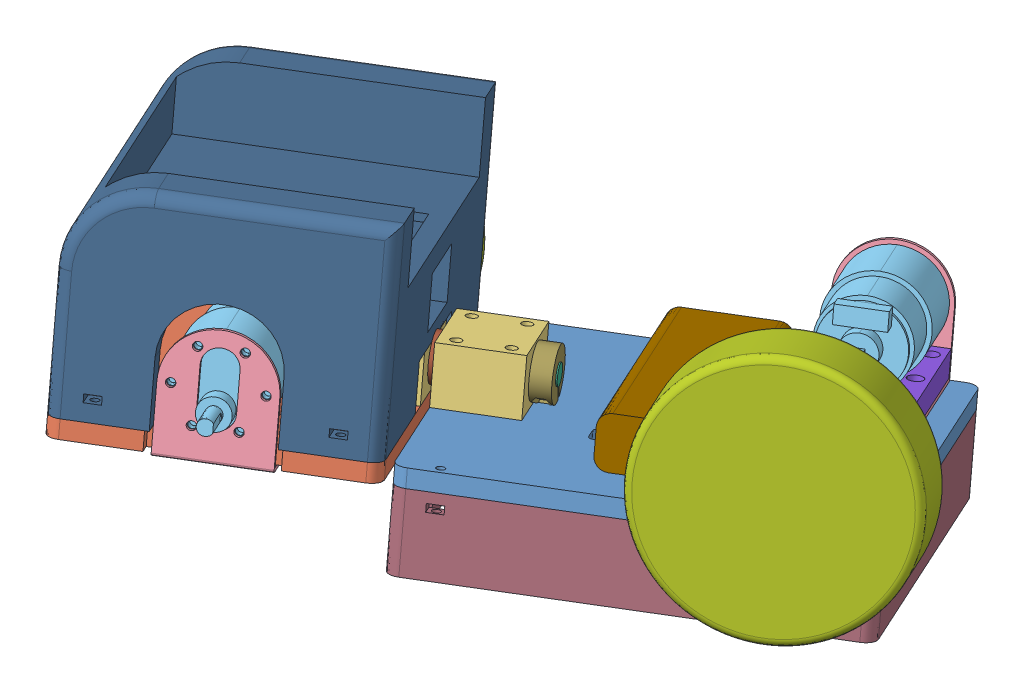
SolidWorks assembly 整车装配体, configuration 默认. Lengths in mm.
Overall size (378.96 184.31 287).
28 component instances, 16 part files, 74 mates.
Components (placement in the parent):
- 底盘-1: 底盘 [默认] at (692.6864 582.8869 540.7098) x (-0.51896 -0.27372 -0.809789) z (0.844115 -0.014792 -0.535958) size (150 7 160)
- 前底盘-1: 前底盘 [默认] at (576.1985 584.9282 614.672) x (0.51896 0.27372 0.809789) z (-0.844115 0.014792 0.535958) size (150 7 110)
- 轴承滑块-1: 轴承滑块 [默认] at (633.9119 611.7376 568.6239) x (0.51896 0.27372 0.809789) z (0.844115 -0.014792 -0.535958) size (34 22 30)
- 轴承滑块-2: 轴承滑块 [默认] at (606.0561 612.2257 586.3106) x (-0.51896 -0.27372 -0.809789) z (-0.844115 0.014792 0.535958) size (34 22 30)
- 37电机支架-1: 37电机支架 [默认] at (554.8799 562.9346 544.3865) x (0.51896 0.27372 0.809789) z (-0.844115 0.014792 0.535958) size (41 45.5 40)
- mg513-30F_电机-1: mg513-30F_电机 [默认] at (610.5897 627.8536 667.6522) x (-0.134724 0.961696 -0.238728) z (-0.844115 0.014792 0.535958) size (36.6 73.4 36.6)
- 37电机支架-2: 37电机支架 [默认] at (712.4284 568.328 441.5972) x (0.51896 0.27372 0.809789) z (-0.844115 0.014792 0.535958) size (41 45.5 40)
- mg513-30F_电机-2: mg513-30F_电机 [默认] at (768.1382 633.2471 564.8629) x (-0.134724 0.961696 -0.238728) z (-0.844115 0.014792 0.535958) size (36.6 73.4 36.6)
- 37电机支架-3: 37电机支架 [默认] at (755.4698 609.4303 582.8843) x (-0.51896 -0.27372 -0.809789) z (0.844115 -0.014792 -0.535958) size (41 45.5 40)
- mg513-30F_电机-3: mg513-30F_电机 [默认] at (692.8891 593.5577 447.4435) x (-0.134724 0.961696 -0.238728) z (0.844115 -0.014792 -0.535958) size (36.6 73.4 36.6)
- 37电机支架-4: 37电机支架 [默认] at (597.9213 604.0368 685.6736) x (-0.51896 -0.27372 -0.809789) z (0.844115 -0.014792 -0.535958) size (41 45.5 40)
- mg513-30F_电机-4: mg513-30F_电机 [默认] at (535.3406 588.1642 550.2328) x (-0.134724 0.961696 -0.238728) z (0.844115 -0.014792 -0.535958) size (36.6 73.4 36.6)
- 连接轴-1: 连接轴 [默认] at (587.2793 602.0021 601.7996) x (0.844115 -0.014792 -0.535958) z (-0.047885 0.993545 -0.102839) size (80 8 8)
- 轮子-1: 轮子 [默认] at (674.6306 576.6982 419.1524) x (0.51896 0.27372 0.809789) z (-0.251206 -0.856676 0.450556) size (30 98 98) (hidden)
- 轮子-2: 轮子 [默认] at (630.7343 631.2494 699.2855) x (-0.51896 -0.27372 -0.809789) z (0.272781 -0.950844 0.146585) size (30 98 98) (hidden)
- 轮子-3: 轮子 [默认] at (788.2828 636.6429 596.4962) x (-0.51896 -0.27372 -0.809789) z (-0.841816 -0.000828 0.539764) size (30 98 98)
- 轮子-4: 轮子 [默认] at (517.0821 571.3047 521.9417) x (0.51896 0.27372 0.809789) z (0.602725 0.554588 -0.57372) size (30 98 98)
- 电机支撑件-3: 电机支撑件 [默认] at (771.3716 610.1664 570.5924) x (-0.51896 -0.27372 -0.809789) z (0.844115 -0.014792 -0.535958) size (145 11.59 40)
- 电机支撑件_前-1: 电机支撑件_前 [默认] at (612.678 612.9474 671.3525) x (-0.51896 -0.27372 -0.809789) z (0.844115 -0.014792 -0.535958) size (145 11.5 40) (hidden)
- 电池-1: 电池 [默认] at (681.0486 594.1442 479.5269) x (0.51896 0.27372 0.809789) z (0.844115 -0.014792 -0.535958) size (106 20 42)
- pcb板子-1: pcb板子 [默认] at (397.0351 450.2511 715.159) x (0.51896 0.27372 0.809789) z (0.844115 -0.014792 -0.535958) size (100 3 100) (hidden)
- 前载物台-1: 前载物台 [默认] at (575.2555 591.6601 613.0009) x (0.51896 0.27372 0.809789) z (-0.844115 0.014792 0.535958) size (150 80 110)
- 轴固定块2-1: 轴固定块2 [默认] at (656.2905 590.2401 561.5489) x (0.51896 0.27372 0.809789) z (-0.844115 0.014792 0.535958) size (34 22 8) (hidden)
- 中间挡块-1: 中间挡块 [默认] at (622.7322 601.3808 579.2893) x (0.5361 0.008129 0.844115) z (-0.844115 0.014792 0.535958) size (18 18 3)
- 轴固定块2-2: 轴固定块2 [默认] at (596.3583 591.2903 599.6019) x (0.51896 0.27372 0.809789) z (-0.844115 0.014792 0.535958) size (34 22 8) (hidden)
- 轴档块-1: 轴档块 [默认] at (654.3865 600.8261 559.1909) x (0.533607 -0.074295 0.842463) z (-0.844115 0.014792 0.535958) size (20 19.97 7.5)
- 轴档块-2: 轴档块 [默认] at (594.8764 601.869 596.9759) x (0.533607 -0.074295 0.842463) z (-0.844115 0.014792 0.535958) size (20 19.97 7.5)
- hou载物台-3: hou载物台 [默认] at (696.7281 554.036 547.8716) x (0.51896 0.27372 0.809789) z (-0.844115 0.014792 0.535958) size (150 30 160)
Mates (geometry in assembly coordinates):
- 重合1: coincident anti-aligned: plane of 前底盘-1 through (575.2555 591.6601 613.0009) normal (-0.134724 0.961696 -0.238728); plane of 轴承滑块-2 through (609.0201 591.0684 591.5626) normal (0.134724 -0.961696 0.238728)
- 同心1: concentric anti-aligned: cylinder of 前底盘-1 through (611.3327 580.9188 578.6926) axis (-0.134724 0.961696 -0.238728) radius 2.2; cylinder of 轴承滑块-2 through (607.4257 608.808 571.7695) axis (0.134724 -0.961696 0.238728) radius 2.15
- 同心2: concentric anti-aligned: cylinder of 前底盘-1 through (608.5936 587.7543 607.7748) axis (-0.134724 0.961696 -0.238728) radius 2.2; cylinder of 轴承滑块-2 through (604.6866 615.6435 600.8516) axis (0.134724 -0.961696 0.238728) radius 2.15
- 重合2: coincident anti-aligned: plane of 底盘-1 through (691.7433 589.6188 539.0387) normal (-0.134724 0.961696 -0.238728); plane of 轴承滑块-1 through (636.8759 590.5803 573.876) normal (0.134724 -0.961696 0.238728)
- 同心5: concentric anti-aligned: cylinder of 底盘-1 through (651.6435 586.9999 580.4409) axis (-0.134724 0.961696 -0.238728) radius 2.2; cylinder of 轴承滑块-1 through (647.7365 614.8891 573.5178) axis (0.134724 -0.961696 0.238728) radius 2.15
- 同心6: concentric anti-aligned: cylinder of 底盘-1 through (623.9944 580.6969 570.6532) axis (-0.134724 0.961696 -0.238728) radius 2.02; cylinder of 轴承滑块-1 through (620.0874 608.5861 563.7301) axis (0.134724 -0.961696 0.238728) radius 2.15
- 同心7: concentric anti-aligned: cylinder of 轴承滑块-1 through (622.7322 601.3808 579.2893) axis (0.844115 -0.014792 -0.535958) radius 4; cylinder of 轴承滑块-2 through (620.1998 601.4252 580.8972) axis (-0.844115 0.014792 0.535958) radius 4
- 重合8: coincident anti-aligned: plane of 底盘-1 through (691.7433 589.6188 539.0387) normal (-0.134724 0.961696 -0.238728); plane of 37电机支架-3 through (734.1925 598.2078 549.683) normal (0.134724 -0.961696 0.238728)
- 同心16: concentric anti-aligned: cylinder of 底盘-1 through (768.8312 593.1479 539.0739) axis (-0.134724 0.961696 -0.238728) radius 1.65; cylinder of 37电机支架-3 through (767.8882 599.8798 537.4028) axis (0.134724 -0.961696 0.238728) radius 1.85
- 同心17: concentric anti-aligned: cylinder of 底盘-1 through (755.9628 600.161 574.5875) axis (-0.134724 0.961696 -0.238728) radius 1.65; cylinder of 37电机支架-3 through (755.0198 606.8929 572.9164) axis (0.134724 -0.961696 0.238728) radius 1.85
- 重合10: coincident anti-aligned: plane of 底盘-1 through (691.7433 589.6188 539.0387) normal (-0.134724 0.961696 -0.238728); plane of 37电机支架-2 through (733.7057 579.5506 474.7986) normal (0.134724 -0.961696 0.238728)
- 同心20: concentric anti-aligned: cylinder of 底盘-1 through (688.498 564.5774 469.315) axis (-0.134724 0.961696 -0.238728) radius 1.65; cylinder of 37电机支架-2 through (687.555 571.3092 467.6439) axis (0.134724 -0.961696 0.238728) radius 1.85
- 同心21: concentric anti-aligned: cylinder of 底盘-1 through (726.2765 570.7029 472.6712) axis (-0.134724 0.961696 -0.238728) radius 1.65; cylinder of 37电机支架-2 through (725.3335 577.4348 471.0001) axis (0.134724 -0.961696 0.238728) radius 1.85
- 重合11: coincident anti-aligned: plane of 37电机支架-1 through (521.6916 565.3794 566.6814) normal (0.51896 0.27372 0.809789); plane of mg513-30F_电机-4 through (535.3406 588.1642 550.2328) normal (-0.51896 -0.27372 -0.809789)
- 同心22: concentric aligned: cylinder of 37电机支架-1 through (542.9125 574.7298 548.069) axis (-0.51896 -0.27372 -0.809789) radius 1.7; cylinder of mg513-30F_电机-4 through (543.6909 575.1404 549.2837) axis (-0.51896 -0.27372 -0.809789) radius 1.5
- 同心23: concentric aligned: cylinder of 37电机支架-1 through (526.2118 600.7775 549.9673) axis (-0.51896 -0.27372 -0.809789) radius 1.7; cylinder of mg513-30F_电机-4 through (526.9902 601.1881 551.182) axis (-0.51896 -0.27372 -0.809789) radius 1.5
- 重合12: coincident anti-aligned: plane of mg513-30F_电机-1 through (610.5897 627.8536 667.6522) normal (0.51896 0.27372 0.809789); plane of 37电机支架-4 through (630.7054 604.4771 662.6625) normal (-0.51896 -0.27372 -0.809789)
- 重合13: coincident anti-aligned: plane of mg513-30F_电机-2 through (768.1382 633.2471 564.8629) normal (0.51896 0.27372 0.809789); plane of 37电机支架-3 through (788.2539 609.8706 559.8732) normal (-0.51896 -0.27372 -0.809789)
- 同心28: concentric aligned: cylinder of mg513-30F_电机-2 through (763.4048 620.4525 572.2211) axis (0.51896 0.27372 0.809789) radius 1.5; cylinder of 37电机支架-3 through (764.1832 620.8631 573.4358) axis (0.51896 0.27372 0.809789) radius 1.7
- 同心29: concentric aligned: cylinder of mg513-30F_电机-2 through (772.8717 646.0417 557.5047) axis (0.51896 0.27372 0.809789) radius 1.5; cylinder of 37电机支架-3 through (773.6501 646.4523 558.7194) axis (0.51896 0.27372 0.809789) radius 1.7
- 重合14: coincident anti-aligned: plane of 37电机支架-2 through (679.2401 570.7728 463.8922) normal (0.51896 0.27372 0.809789); plane of mg513-30F_电机-3 through (692.8891 593.5577 447.4435) normal (-0.51896 -0.27372 -0.809789)
- 同心30: concentric aligned: cylinder of 37电机支架-2 through (700.461 580.1233 445.2797) axis (-0.51896 -0.27372 -0.809789) radius 1.7; cylinder of mg513-30F_电机-3 through (701.2394 580.5338 446.4944) axis (-0.51896 -0.27372 -0.809789) radius 1.5
- 同心31: concentric aligned: cylinder of 37电机支架-2 through (683.7603 606.171 447.178) axis (-0.51896 -0.27372 -0.809789) radius 1.7; cylinder of mg513-30F_电机-3 through (684.5387 606.5816 448.3927) axis (-0.51896 -0.27372 -0.809789) radius 1.5
- 同心32: concentric anti-aligned: cylinder of 轴承滑块-1 through (622.7322 601.3808 579.2893) axis (0.844115 -0.014792 -0.535958) radius 4; cylinder of 连接轴-1 through (654.8085 600.8187 558.9229) axis (-0.844115 0.014792 0.535958) radius 4
- 同心33: concentric aligned: cylinder of 轴承滑块-2 through (620.1998 601.4252 580.8972) axis (-0.844115 0.014792 0.535958) radius 4; cylinder of 连接轴-1 through (654.8085 600.8187 558.9229) axis (-0.844115 0.014792 0.535958) radius 4
- 同心34: concentric anti-aligned: cylinder of mg513-30F_电机-3 through (690.7184 585.1835 444.2559) axis (-0.51896 -0.27372 -0.809789) radius 3; cylinder of 轮子-1 through (683.9719 581.6251 433.7286) axis (0.51896 0.27372 0.809789) radius 2.5
- 重合17: coincident anti-aligned: plane of mg513-30F_电机-3 through (683.0288 588.357 432.0575) normal (-0.51896 -0.27372 -0.809789); plane of 轮子-1 through (683.9719 581.6251 433.7286) normal (0.51896 0.27372 0.809789)
- 同心35: concentric anti-aligned: cylinder of mg513-30F_电机-4 through (533.1699 579.79 547.0452) axis (-0.51896 -0.27372 -0.809789) radius 3; cylinder of 轮子-4 through (526.4234 576.2317 536.5179) axis (0.51896 0.27372 0.809789) radius 2.5
- 重合18: coincident anti-aligned: plane of mg513-30F_电机-4 through (525.4803 582.9635 534.8468) normal (-0.51896 -0.27372 -0.809789); plane of 轮子-4 through (526.4234 576.2317 536.5179) normal (0.51896 0.27372 0.809789)
- 同心36: concentric anti-aligned: cylinder of mg513-30F_电机-2 through (772.195 628.1576 571.3927) axis (0.51896 0.27372 0.809789) radius 3; cylinder of 轮子-3 through (778.9415 631.7159 581.92) axis (-0.51896 -0.27372 -0.809789) radius 2.5
- 重合19: coincident anti-aligned: plane of mg513-30F_电机-2 through (777.9985 638.4478 580.2489) normal (0.51896 0.27372 0.809789); plane of 轮子-3 through (778.9415 631.7159 581.92) normal (-0.51896 -0.27372 -0.809789)
- 同心37: concentric anti-aligned: cylinder of mg513-30F_电机-1 through (614.6466 622.7641 674.182) axis (0.51896 0.27372 0.809789) radius 3; cylinder of 轮子-2 through (621.393 626.3225 684.7093) axis (-0.51896 -0.27372 -0.809789) radius 2.5
- 重合20: coincident anti-aligned: plane of mg513-30F_电机-1 through (620.45 633.0543 683.0382) normal (0.51896 0.27372 0.809789); plane of 轮子-2 through (621.393 626.3225 684.7093) normal (-0.51896 -0.27372 -0.809789)
- 重合27: coincident anti-aligned: plane of 37电机支架-3 through (767.755 599.0586 527.8866) normal (-0.134724 0.961696 -0.238728); plane of 电机支撑件-3 through (713.0047 570.1812 442.4538) normal (0.134724 -0.961696 0.238728)
- 重合28: coincident anti-aligned: plane of 37电机支架-3 through (788.2539 609.8706 559.8732) normal (-0.51896 -0.27372 -0.809789); plane of 电机支撑件-3 through (768.0709 633.728 564.7436) normal (0.51896 0.27372 0.809789)
- 同心44: concentric aligned: cylinder of 37电机支架-3 through (780.3432 606.4491 556.8377) axis (0.134724 -0.961696 0.238728) radius 1.85; cylinder of 电机支撑件-3 through (778.7939 617.5086 554.0923) axis (0.134724 -0.961696 0.238728) radius 3
- 同心45: concentric aligned: cylinder of 37电机支架-3 through (767.8882 599.8798 537.4028) axis (0.134724 -0.961696 0.238728) radius 1.85; cylinder of 电机支撑件-3 through (766.3388 610.9393 534.6574) axis (0.134724 -0.961696 0.238728) radius 3
- 重合30: coincident anti-aligned: plane of 37电机支架-1 through (521.6916 565.3794 566.6814) normal (0.51896 0.27372 0.809789); plane of 电机支撑件_前-1 through (534.1281 596.8195 548.0843) normal (-0.51896 -0.27372 -0.809789)
- 同心46: concentric aligned: cylinder of 37电机支架-1 through (542.4615 572.4851 589.8681) axis (0.134724 -0.961696 0.238728) radius 1.85; cylinder of 电机支撑件_前-1 through (539.7671 591.719 585.0935) axis (0.134724 -0.961696 0.238728) radius 3
- 重合31: coincident anti-aligned: plane of 底盘-1 through (691.7433 589.6188 539.0387) normal (-0.134724 0.961696 -0.238728); plane of 电池-1 through (683.7431 574.9103 484.3015) normal (0.134724 -0.961696 0.238728)
- 平行3: parallel aligned: plane of 底盘-1 through (663.1361 611.3312 642.6495) normal (0.51896 0.27372 0.809789); plane of 电池-1 through (738.7528 603.9246 570.1391) normal (0.51896 0.27372 0.809789)
- 平行4: parallel anti-aligned: plane of 底盘-1 through (691.7433 589.6188 539.0387) normal (-0.134724 0.961696 -0.238728); plane of pcb板子-1 through (397.4393 447.366 715.8752) normal (0.134724 -0.961696 0.238728)
- 平行5: parallel aligned: plane of 底盘-1 through (663.1361 611.3312 642.6495) normal (0.51896 0.27372 0.809789); plane of pcb板子-1 through (381.1815 461.7916 783.1625) normal (0.51896 0.27372 0.809789)
- 重合35: coincident aligned: plane of 底盘-1 through (692.6864 582.8869 540.7098) normal (0.134724 -0.961696 0.238728); plane of 前底盘-1 through (576.1985 584.9282 614.672) normal (0.134724 -0.961696 0.238728)
- 重合36: coincident anti-aligned: plane of 前底盘-1 through (575.2555 591.6601 613.0009) normal (-0.134724 0.961696 -0.238728); plane of 前载物台-1 through (575.2555 591.6601 613.0009) normal (0.134724 -0.961696 0.238728)
- 重合37: coincident aligned: plane of 前底盘-1 through (660.6038 611.3755 644.2574) normal (0.51896 0.27372 0.809789); plane of 前载物台-1 through (649.8259 688.3112 625.1591) normal (0.51896 0.27372 0.809789)
- 重合38: coincident aligned: plane of 前底盘-1 through (489.9072 571.9447 581.7444) normal (-0.844115 0.014792 0.535958); plane of 前载物台-1 through (479.1292 648.8803 562.6462) normal (-0.844115 0.014792 0.535958)
- 同心50: concentric aligned: cylinder of 连接轴-1 through (654.8085 600.8187 558.9229) axis (-0.844115 0.014792 0.535958) radius 4; cylinder of 中间挡块-1 through (622.7322 601.3808 579.2893) axis (-0.844115 0.014792 0.535958) radius 4.15
- 重合42: coincident anti-aligned: plane of 轴承滑块-2 through (630.5041 595.4998 597.2896) normal (0.844115 -0.014792 -0.535958); plane of 中间挡块-1 through (620.1998 601.4252 580.8972) normal (-0.844115 0.014792 0.535958)
- 重合43: coincident anti-aligned: plane of 轴承滑块-1 through (615.3918 586.1489 568.1489) normal (-0.844115 0.014792 0.535958); plane of 中间挡块-1 through (622.7322 601.3808 579.2893) normal (0.844115 -0.014792 -0.535958)
- 同心51: concentric aligned: cylinder of 连接轴-1 through (654.8085 600.8187 558.9229) axis (-0.844115 0.014792 0.535958) radius 4; cylinder of 轴固定块2-1 through (654.8085 600.8187 558.9229) axis (-0.844115 0.014792 0.535958) radius 4
- 重合44: coincident aligned: plane of 连接轴-1 through (654.8085 600.8187 558.9229) normal (0.844115 -0.014792 -0.535958); plane of 轴固定块2-1 through (656.2905 590.2401 561.5489) normal (0.844115 -0.014792 -0.535958)
- 重合49: coincident anti-aligned: plane of 底盘-1 through (691.7433 589.6188 539.0387) normal (-0.134724 0.961696 -0.238728); plane of 轴固定块2-1 through (658.3599 595.0116 579.603) normal (0.134724 -0.961696 0.238728)
- 重合50: coincident anti-aligned: plane of 轴承滑块-1 through (640.7153 585.7051 552.0702) normal (0.844115 -0.014792 -0.535958); plane of 轴固定块2-1 through (649.5376 590.3584 565.8366) normal (-0.844115 0.014792 0.535958)
- 同心53: concentric aligned: cylinder of 连接轴-1 through (654.8085 600.8187 558.9229) axis (-0.844115 0.014792 0.535958) radius 4; cylinder of 轴固定块2-2 through (594.8764 601.869 596.9759) axis (-0.844115 0.014792 0.535958) radius 4
- 重合51: coincident anti-aligned: plane of 轴承滑块-2 through (605.1807 595.9435 613.3683) normal (-0.844115 0.014792 0.535958); plane of 轴固定块2-2 through (596.3583 591.2903 599.6019) normal (0.844115 -0.014792 -0.535958)
- 重合52: coincident anti-aligned: plane of 前底盘-1 through (575.2555 591.6601 613.0009) normal (-0.134724 0.961696 -0.238728); plane of 轴固定块2-2 through (598.4277 596.0619 617.656) normal (0.134724 -0.961696 0.238728)
- 同心54: concentric anti-aligned: cylinder of 连接轴-1 through (654.8085 600.8187 558.9229) axis (-0.844115 0.014792 0.535958) radius 4; cylinder of 轴档块-1 through (648.0556 600.937 563.2106) axis (0.844115 -0.014792 -0.535958) radius 4
- 重合53: coincident anti-aligned: plane of 轴承滑块-1 through (640.7153 585.7051 552.0702) normal (0.844115 -0.014792 -0.535958); plane of 轴档块-1 through (648.0556 600.937 563.2106) normal (-0.844115 0.014792 0.535958)
- 同心56: concentric anti-aligned: cylinder of 连接轴-1 through (654.8085 600.8187 558.9229) axis (-0.844115 0.014792 0.535958) radius 4; cylinder of 轴档块-2 through (588.5455 601.9799 600.9956) axis (0.844115 -0.014792 -0.535958) radius 4
- 重合54: coincident anti-aligned: plane of 轴承滑块-2 through (605.1807 595.9435 613.3683) normal (-0.844115 0.014792 0.535958); plane of 轴档块-2 through (594.8764 601.869 596.9759) normal (0.844115 -0.014792 -0.535958)
- 同心57: concentric aligned: cylinder of 前底盘-1 through (578.337 611.6859 691.9342) axis (0.134724 -0.961696 0.238728) radius 1.65; cylinder of 前载物台-1 through (576.9898 621.3029 689.5469) axis (0.134724 -0.961696 0.238728) radius 1.65
- 同心58: concentric aligned: cylinder of 前底盘-1 through (572.1739 571.6343 534.0676) axis (0.134724 -0.961696 0.238728) radius 1.65; cylinder of 前载物台-1 through (570.8267 581.2512 531.6803) axis (0.134724 -0.961696 0.238728) radius 1.65
- 同心59: concentric anti-aligned: cylinder of 前底盘-1 through (542.2595 573.9276 589.51) axis (-0.134724 0.961696 -0.238728) radius 1.65; cylinder of 37电机支架-1 through (542.4615 572.4851 589.8681) axis (0.134724 -0.961696 0.238728) radius 1.85
- 重合61: coincident anti-aligned: plane of 前底盘-1 through (576.1985 584.9282 614.672) normal (0.134724 -0.961696 0.238728); plane of 37电机支架-1 through (542.1906 576.1913 598.6681) normal (-0.134724 0.961696 -0.238728)
- 同心60: concentric anti-aligned: cylinder of 前底盘-1 through (555.1279 566.9145 553.9963) axis (-0.134724 0.961696 -0.238728) radius 1.65; cylinder of 37电机支架-1 through (555.33 565.472 554.3544) axis (0.134724 -0.961696 0.238728) radius 1.85
- 重合62: coincident anti-aligned: plane of 前底盘-1 through (576.1985 584.9282 614.672) normal (0.134724 -0.961696 0.238728); plane of 37电机支架-4 through (610.2065 593.6652 630.6759) normal (-0.134724 0.961696 -0.238728)
- 同心61: concentric anti-aligned: cylinder of 前底盘-1 through (597.2692 602.9419 675.3476) axis (-0.134724 0.961696 -0.238728) radius 1.65; cylinder of 37电机支架-4 through (597.4713 601.4994 675.7057) axis (0.134724 -0.961696 0.238728) radius 1.85
- 同心64: concentric anti-aligned: cylinder of 前底盘-1 through (610.1376 595.9289 639.834) axis (-0.134724 0.961696 -0.238728) radius 1.65; cylinder of 37电机支架-4 through (610.3397 594.4863 640.192) axis (0.134724 -0.961696 0.238728) radius 1.85
- 同心65: concentric aligned: cylinder of mg513-30F_电机-1 through (615.3232 640.6482 660.294) axis (0.51896 0.27372 0.809789) radius 1.5; cylinder of 37电机支架-4 through (616.1016 641.0588 661.5087) axis (0.51896 0.27372 0.809789) radius 1.7
- 同心66: concentric aligned: cylinder of mg513-30F_电机-1 through (602.2394 640.8775 668.6013) axis (0.51896 0.27372 0.809789) radius 1.5; cylinder of 37电机支架-4 through (603.0178 641.2881 669.816) axis (0.51896 0.27372 0.809789) radius 1.7
- 重合63: coincident anti-aligned: plane of 底盘-1 through (692.6864 582.8869 540.7098) normal (0.134724 -0.961696 0.238728); plane of hou载物台-3 through (692.6864 582.8869 540.7098) normal (-0.134724 0.961696 -0.238728)
- 重合64: coincident aligned: plane of 底盘-1 through (663.1361 611.3312 642.6495) normal (-0.844115 0.014792 0.535958); plane of hou载物台-3 through (586.2352 563.5413 522.8522) normal (-0.844115 0.014792 0.535958)
- 重合65: coincident aligned: plane of 底盘-1 through (663.1361 611.3312 642.6495) normal (0.51896 0.27372 0.809789); plane of hou载物台-3 through (799.1376 602.2325 558.5673) normal (0.51896 0.27372 0.809789)
